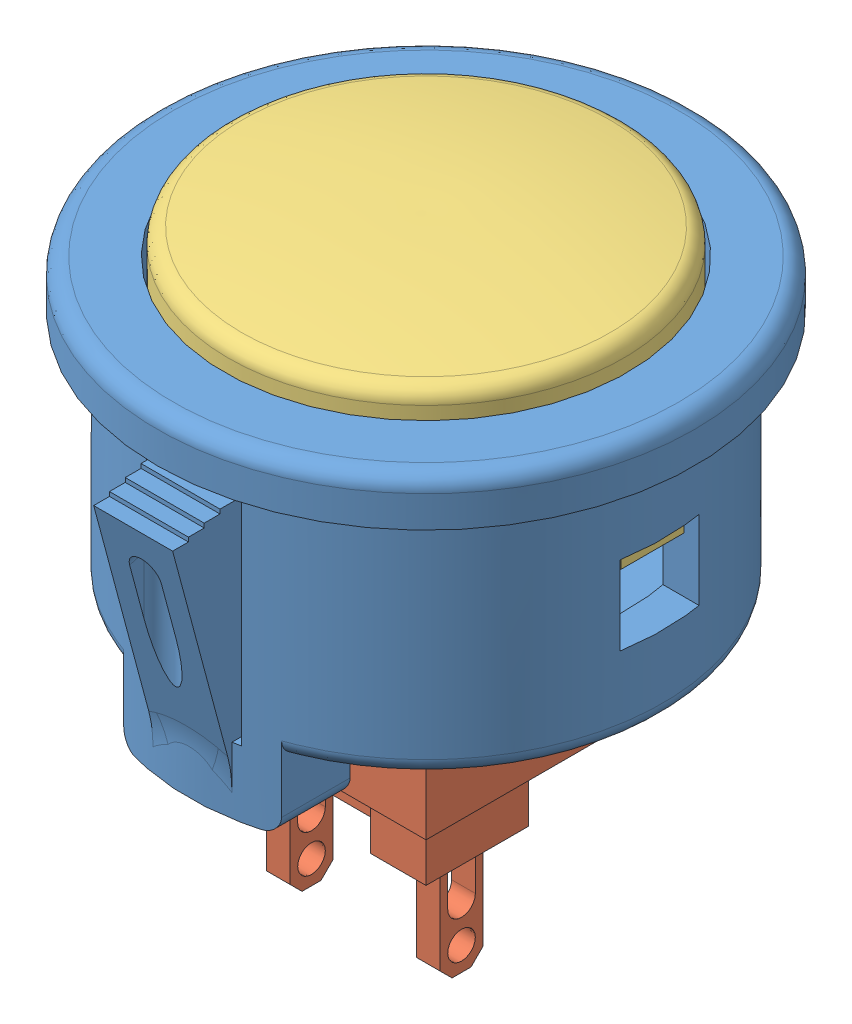
SolidWorks assembly sanwa_button_00_asm_6, configuration Predeterminado. Lengths in mm.
Overall size (34 37.41 37.09).
3 component instances, 3 part files, 0 mates.
Components (placement in the parent):
- sanwa_button_00_11-1: sanwa_button_00_11 [Predeterminado] at origin size (34 22.2 37.09)
- black_00_3-1: black_00_3 [Predeterminado] at (0 5 0) x (-1 0 0) z (0 0 1) size (14 26.9 14)
- sanwa_button_02_8-1: sanwa_button_02_8 [Predeterminado] at (0 17 0) x (0 0 -1) z (1 0 0) size (25 13.51 28.68)
